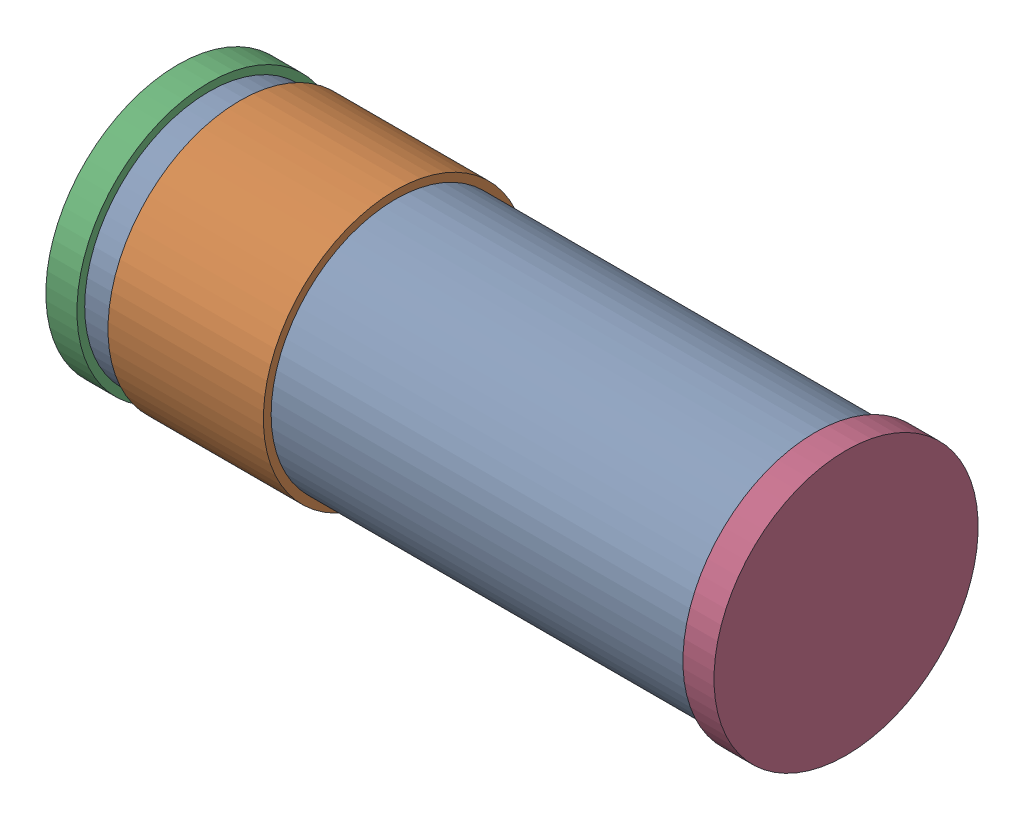
SolidWorks assembly D9, configuration Default. Lengths in mm.
Overall size (4.3 1.7 1.7).
8 component instances, 4 part files, 0 mates.
Components (placement in the parent):
- 756964128-1: 756964128 [Default] at (9.6999 28.4999 -1.7115) x (0 1 0) z (-1 0 0) size (1.6 1.6 4)
  - Cylinder (7)-1: Cylinder (7) [Default] at origin size (1.6 1.6 4)
- 756964008-1: 756964008 [Default] at (6.9499 28.4999 -1.7115) x (0 1 0) z (-1 0 0) size (1.7 1.7 1)
  - Cylinder (8)-1: Cylinder (8) [Default] at origin size (1.7 1.7 1)
- 756963888-1: 756963888 [Default] at (5.7499 28.4999 -1.7115) x (0 1 0) z (-1 0 0) size (1.7 1.7 0.2)
  - Cylinder (9)-1: Cylinder (9) [Default] at origin size (1.7 1.7 0.2)
- 756963768-1: 756963768 [Default] at (9.6501 28.4998 -1.7115) x (0 1 0) z (1 0 0) size (1.7 1.7 0.2)
  - Cylinder (10)-1: Cylinder (10) [Default] at origin size (1.7 1.7 0.2)
